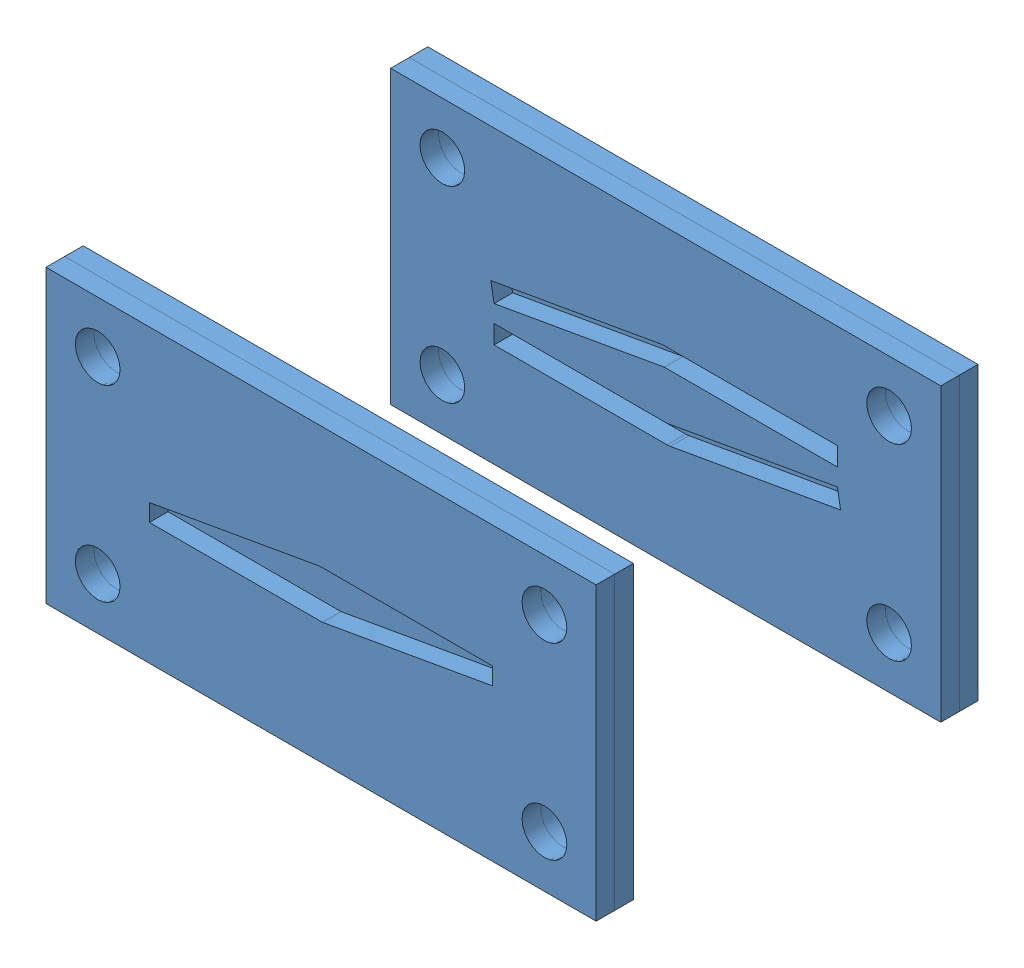
SolidWorks assembly Assem2, configuration Default. Lengths in mm.
Overall size (79.81 42.26 55.4).
4 component instances, 1 part files, 7 mates.
Components (placement in the parent):
- Part1-1: Part1 [black Front] at (-62.8275 13.9169 20.5233) size (79.81 42.26 2.7)
- Part1-2: Part1 [Clear Back] at (-62.8275 13.9169 23.2233) size (79.81 42.26 2.7)
- Part1-3: Part1 [black Front] at (-62.8275 13.9169 73.2233) size (79.81 42.26 2.7)
- Part1-4: Part1 [Clear Back] at (-62.8275 13.9169 70.5233) size (79.81 42.26 2.7)
Mates (geometry in assembly coordinates):
- Coincident1: coincident aligned: line of Part1-1 through (-22.9226 35.0458 23.2233) axis (-1 0 0); line of Part1-2 through (-22.9226 35.0458 23.2233) axis (-1 0 0)
- Coincident2: coincident aligned: line of Part1-3 through (-22.9226 35.0458 73.2233) axis (-1 0 0); line of Part1-4 through (-22.9226 35.0458 73.2233) axis (-1 0 0)
- Parallel1: parallel aligned: line of Part1-2 through (-22.9226 35.0458 25.9233) axis (-1 0 0); line of Part1-4 through (-22.9226 35.0458 70.5233) axis (-1 0 0)
- Parallel2: parallel aligned: line of Part1-2 through (-22.9226 -7.212 25.9233) axis (0 1 0); line of Part1-4 through (-22.9226 -7.212 70.5233) axis (0 1 0)
- Coincident5: coincident aligned: plane of Part1-2 through (-102.7324 35.0458 25.9233) normal (0 1 0); plane of Part1-3 through (-102.7324 35.0458 75.9233) normal (0 1 0)
- Coincident6: coincident aligned: plane of Part1-1 through (-102.7324 35.0458 23.2233) normal (-1 0 0); plane of Part1-3 through (-102.7324 35.0458 75.9233) normal (-1 0 0)
- Distance1: distance = 50 mm anti-aligned: plane of Part1-1 through (-62.8275 13.9169 23.2233) normal (0 0 1); plane of Part1-3 through (-62.8275 13.9169 73.2233) normal (0 0 -1)
